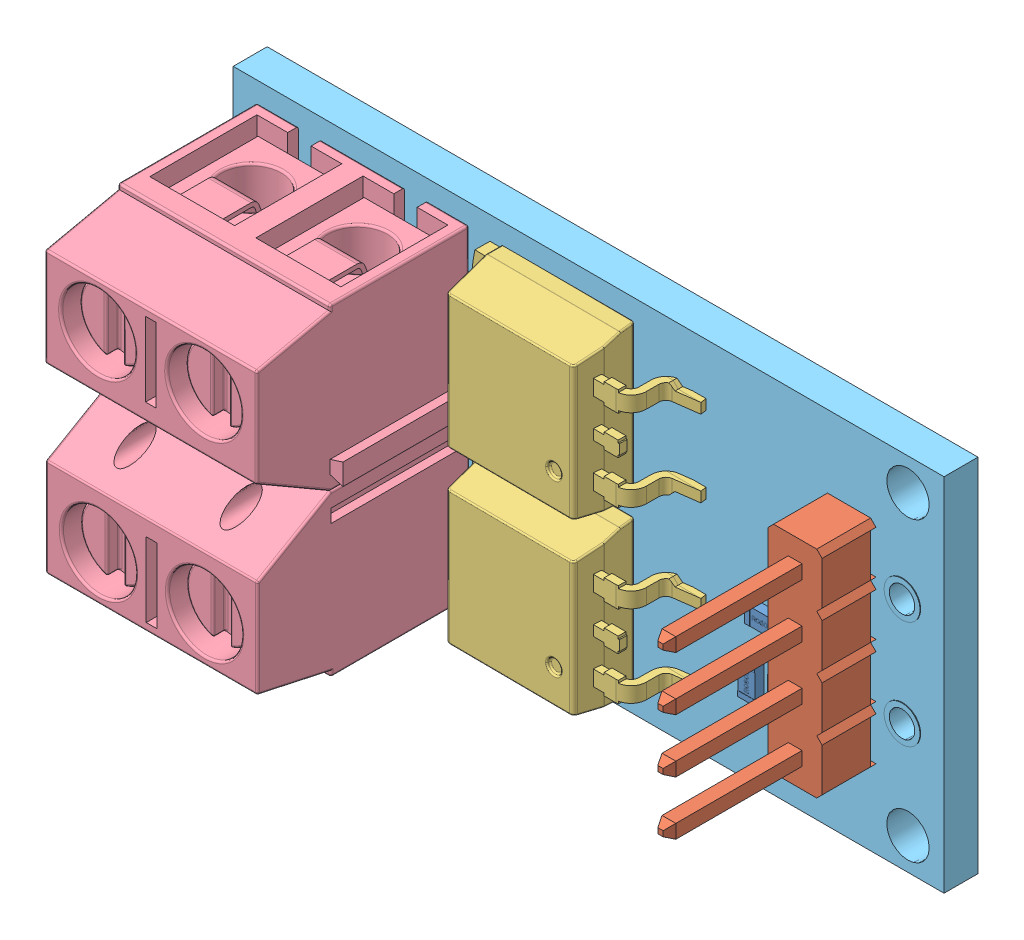
SolidWorks assembly PWM Mosfet Modul 400W, configuration Predeterminado. Lengths in mm.
Overall size (33.5 17 14.1).
11 component instances, 5 part files, 0 mates.
Components (placement in the parent):
- PWM Mosfet Modul 400W.step-1: PWM Mosfet Modul 400W.step [Predeterminado] at origin size (33.5 17 14.1)
  - Components.step-1: Components.step [Predeterminado] at origin size (29.75 15.18 14.1)
    - r-smd-0603.step-1: r-smd-0603.step [Predeterminado] at (9.281 -4.0736 1.6099) x (0 1 0) z (1 0 0) size (1.6 0.45 0.8)
    - PinHeader.step-1: PinHeader.step [Predeterminado] at (13.55 6.3633 1.6067) x (0 -1 0) z (-1 0 0) size (10.16 11.94 2.54)
    - r-smd-0603.step-2: r-smd-0603.step [Predeterminado] at (7.881 -4.0736 1.6099) x (0 1 0) z (1 0 0) size (1.6 0.45 0.8)
    - r-smd-0603.step-3: r-smd-0603.step [Predeterminado] at (8.603 -1.3259 1.6099) x (1 0 0) z (0 -1 0) size (1.6 0.45 0.8)
    - MOS.step-1: MOS.step [Predeterminado] at (0.2016 -3.5972 0.8) x (0 1 0) z (0 0 1) size (7 10.4 3.01)
    - MOS.step-2: MOS.step [Predeterminado] at (0.2016 4.4028 0.8) x (0 1 0) z (0 0 1) size (7 10.4 3.01)
    - tb5p-2p_p5_l10_w7-6_h10 v1.step-1: tb5p-2p_p5_l10_w7-6_h10 v1.step [Predeterminado] at (-10.6 -4.5 6.6) x (1 0 0) z (0 -1 0) size (10.6 14.1 7.6)
    - tb5p-2p_p5_l10_w7-6_h10 v1.step-2: tb5p-2p_p5_l10_w7-6_h10 v1.step [Predeterminado] at (-10.6316 4.4818 6.6) x (-1 0 0) z (0 1 0) size (10.6 14.1 7.6)
  - PWM Mosfet Modul 400W.step-1: PWM Mosfet Modul 400W.step [Predeterminado] at origin size (33.5 17 1.66)
